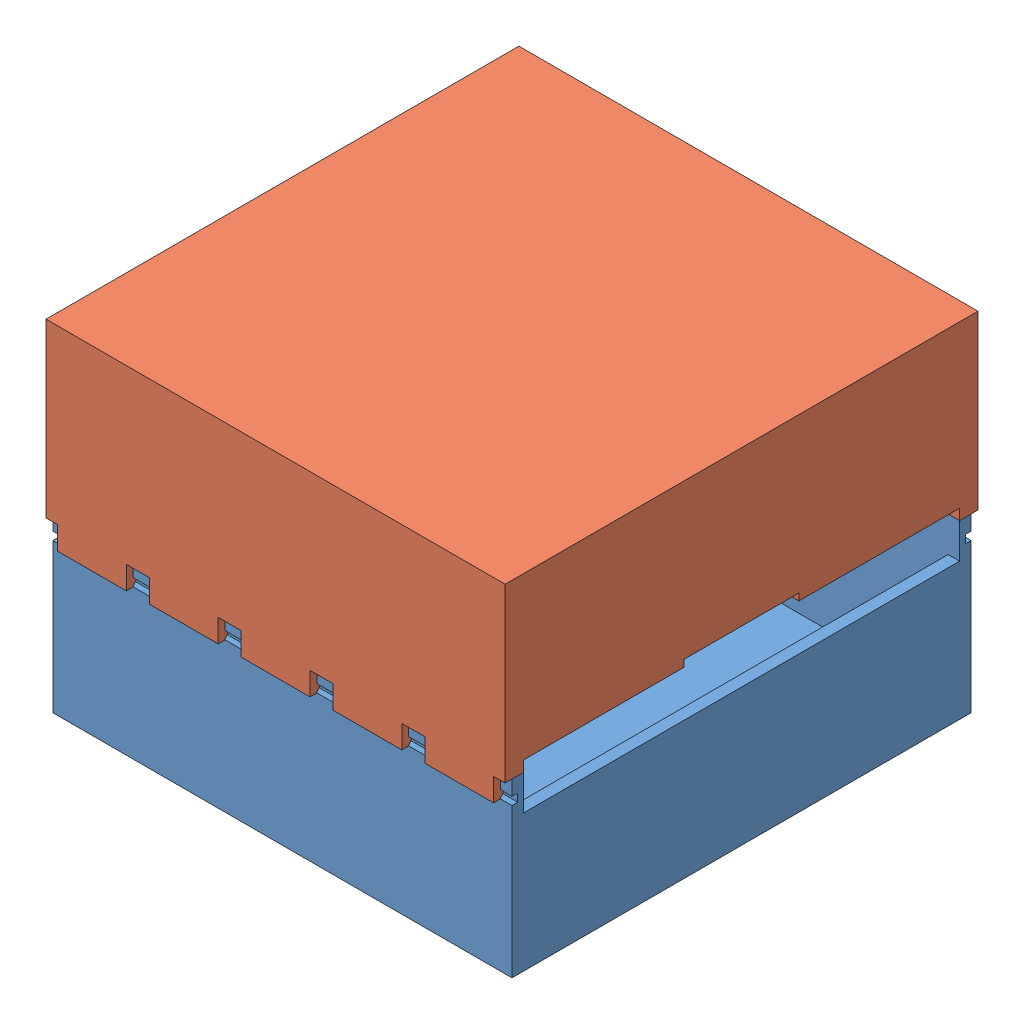
SolidWorks assembly Сборка1, configuration По умолчанию. Lengths in mm.
Overall size (200 150 206).
2 component instances, 2 part files, 3 mates.
Components (placement in the parent):
- BottomPart-1: BottomPart [По умолчанию] at (103.1702 102.5738 103.1702) size (200 75 200)
- Toppart-1: Toppart [По умолчанию] at (103.1702 252.5738 103.1702) x (-1 0 0) z (0 0 1) size (200 85 206)
Mates (geometry in assembly coordinates):
- Совпадение11: coincident anti-aligned: plane of BottomPart-1 through (103.1702 177.5738 103.1702) normal (0 1 0); plane of Toppart-1 through (103.1702 177.5738 103.1702) normal (0 -1 0)
- Совпадение12: coincident anti-aligned: line of BottomPart-1 through (3.1702 177.5738 3.1702) axis (0 0 1); line of Toppart-1 through (3.1702 177.5738 8.1702) axis (0 0 -1)
- Совпадение14: coincident anti-aligned: line of BottomPart-1 through (3.1702 177.5738 8.1702) axis (1 0 0); line of Toppart-1 through (84.1702 177.5738 8.1702) axis (-1 0 0)
